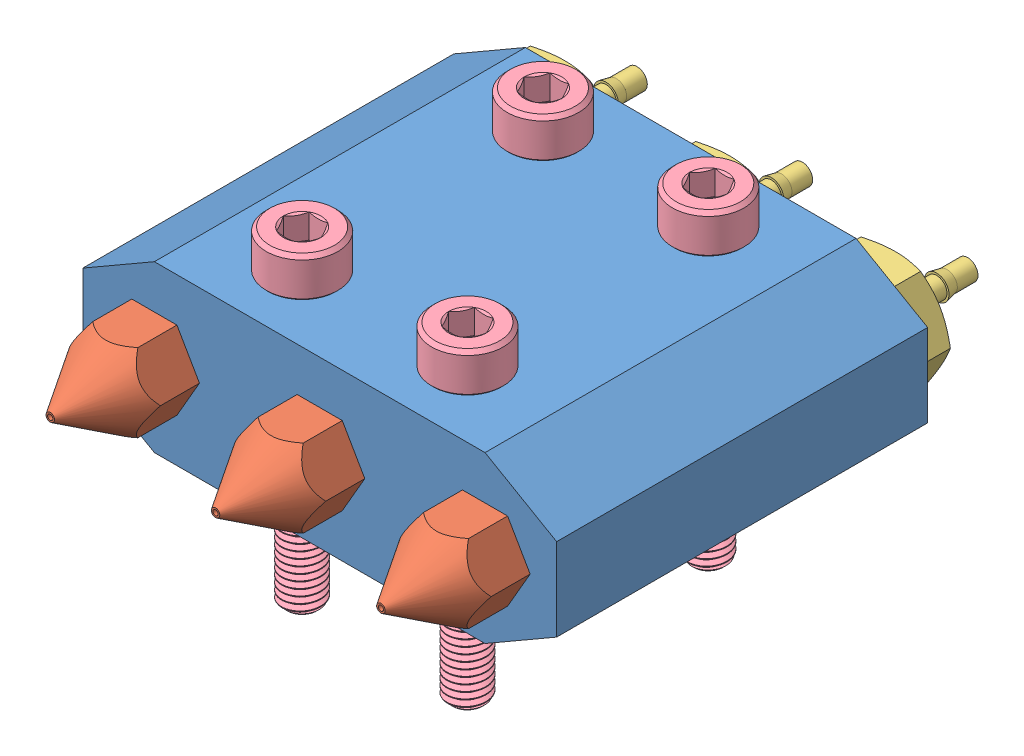
SolidWorks assembly SUB_3 Nozzle Block Assembly, configuration Default. Lengths in mm.
Overall size (36.86 25.38 45.07).
11 component instances, 4 part files, 30 mates.
Components (placement in the parent):
- M22a_3 Nozzle Block-1: M22a_3 Nozzle Block [Default] at (-7.7246 28.2 32.9307) size (36.4 12.7 28.5)
- M20_Creality Brass Nozzle-1: M20_Creality Brass Nozzle [Default] at (-1.3746 34.55 40.9307) x (0.866025 0.5 0) z (0 0 1) size (6 7.32 13)
- M20_Creality Brass Nozzle-2: M20_Creality Brass Nozzle [Default] at (11.3254 34.55 40.9307) x (0.866025 0.5 0) z (0 0 1) size (6 7.32 13)
- M20_Creality Brass Nozzle-3: M20_Creality Brass Nozzle [Default] at (24.0254 34.55 40.9307) x (0.866025 0.5 0) z (0 0 1) size (6 7.32 13)
- M21_5058K956_ALUMINUM LOW-PRESSURE BARBED TUBE FITTING-1: M21_5058K956_ALUMINUM LOW-PRESSURE BARBED TUBE FITTING [5058K956] at (24.0254 34.55 3.3988) x (0 0 -1) z (0.866025 0.5 0) size (15.08 9.17 7.94)
- M21_5058K956_ALUMINUM LOW-PRESSURE BARBED TUBE FITTING-2: M21_5058K956_ALUMINUM LOW-PRESSURE BARBED TUBE FITTING [5058K956] at (-1.3746 34.55 3.3988) x (0 0 -1) z (0.866025 0.5 0) size (15.08 9.17 7.94)
- M21_5058K956_ALUMINUM LOW-PRESSURE BARBED TUBE FITTING-4: M21_5058K956_ALUMINUM LOW-PRESSURE BARBED TUBE FITTING [5058K956] at (11.3254 34.55 3.3988) x (0 0 -1) z (0.866025 0.5 0) size (15.08 9.17 7.94)
- M41_91292A801_18-8 Stainless Steel Socket Head Screw-1: M41_91292A801_18-8 Stainless Steel Socket Head Screw [91292A801] at (4.9754 31.4 27.9307) x (0 0 1) z (0 1 0) size (5.5 5.5 25.38)
- M41_91292A801_18-8 Stainless Steel Socket Head Screw-2: M41_91292A801_18-8 Stainless Steel Socket Head Screw [91292A801] at (4.9754 31.4 9.4307) x (0.866025 0 0.5) z (0 1 0) size (5.5 5.5 25.38)
- M41_91292A801_18-8 Stainless Steel Socket Head Screw-3: M41_91292A801_18-8 Stainless Steel Socket Head Screw [91292A801] at (17.6754 31.4 27.9307) x (0 0 1) z (0 1 0) size (5.5 5.5 25.38)
- M41_91292A801_18-8 Stainless Steel Socket Head Screw-4: M41_91292A801_18-8 Stainless Steel Socket Head Screw [91292A801] at (17.6754 31.4 9.4307) x (-0.866025 0 0.5) z (0 1 0) size (5.5 5.5 25.38)
Mates (geometry in assembly coordinates):
- Concentric1: concentric aligned: cylinder of 3 Nozzle Block-1 through (-1.3746 34.55 32.9307) axis (0 0 1) radius 2.5; cylinder of M20_Creality Brass Nozzle-1 through (-1.3746 34.55 40.9307) axis (0 0 1) radius 3
- Coincident1: coincident anti-aligned: plane of 3 Nozzle Block-1 through (-7.7246 28.2 32.9307) normal (0 0 1); plane of M20_Creality Brass Nozzle-1 through (-3.1067 37.55 32.9307) normal (0 0 -1)
- Parallel1: parallel aligned: plane of 3 Nozzle Block-1 through (-7.7246 40.9 4.4307) normal (0 1 0); plane of M20_Creality Brass Nozzle-1 through (0.3574 37.55 27.9307) normal (0 1 0)
- Concentric2: concentric aligned: cylinder of 3 Nozzle Block-1 through (11.3254 34.55 32.9307) axis (0 0 1) radius 2.5; cylinder of M20_Creality Brass Nozzle-2 through (11.3254 34.55 40.9307) axis (0 0 1) radius 3
- Coincident3: coincident anti-aligned: plane of 3 Nozzle Block-1 through (-7.7246 28.2 32.9307) normal (0 0 1); plane of M20_Creality Brass Nozzle-2 through (9.5933 37.55 32.9307) normal (0 0 -1)
- Parallel2: parallel aligned: plane of 3 Nozzle Block-1 through (-7.7246 40.9 4.4307) normal (0 1 0); plane of M20_Creality Brass Nozzle-2 through (13.0574 37.55 27.9307) normal (0 1 0)
- Concentric3: concentric aligned: cylinder of 3 Nozzle Block-1 through (24.0254 34.55 32.9307) axis (0 0 1) radius 2.5; cylinder of M20_Creality Brass Nozzle-3 through (24.0254 34.55 40.9307) axis (0 0 1) radius 3
- Coincident5: coincident anti-aligned: plane of 3 Nozzle Block-1 through (-7.7246 28.2 32.9307) normal (0 0 1); plane of M20_Creality Brass Nozzle-3 through (22.2933 37.55 32.9307) normal (0 0 -1)
- Parallel3: parallel aligned: plane of M20_Creality Brass Nozzle-3 through (25.7574 37.55 27.9307) normal (0 1 0); plane of 3 Nozzle Block-1 through (-7.7246 40.9 4.4307) normal (0 1 0)
- Concentric4: concentric aligned: cylinder of 3 Nozzle Block-1 through (24.0254 34.55 32.9307) axis (0 0 1) radius 2.5; cylinder of M21_5058K956_ALUMINUM LOW-PRESSURE BARBED TUBE FITTING-1 through (24.0254 34.55 -4.0546) axis (0 0 1) radius 3
- Parallel4: parallel aligned: plane of M21_5058K956_ALUMINUM LOW-PRESSURE BARBED TUBE FITTING-1 through (21.734 38.5187 4.4307) normal (0 1 0); plane of 3 Nozzle Block-1 through (-7.7246 40.9 4.4307) normal (0 1 0)
- Coincident8: coincident anti-aligned: plane of 3 Nozzle Block-1 through (-7.7246 28.2 4.4307) normal (0 0 -1); plane of M21_5058K956_ALUMINUM LOW-PRESSURE BARBED TUBE FITTING-1 through (24.0254 42.4875 4.4307) normal (0 0 1)
- Concentric5: concentric aligned: cylinder of 3 Nozzle Block-1 through (11.3254 34.55 32.9307) axis (0 0 1) radius 2.5; cylinder of M21_5058K956_ALUMINUM LOW-PRESSURE BARBED TUBE FITTING-4 through (11.3254 34.55 -4.0546) axis (0 0 1) radius 3
- Coincident10: coincident anti-aligned: plane of 3 Nozzle Block-1 through (-7.7246 28.2 4.4307) normal (0 0 -1); plane of M21_5058K956_ALUMINUM LOW-PRESSURE BARBED TUBE FITTING-4 through (11.3254 42.4875 4.4307) normal (0 0 1)
- Parallel5: parallel aligned: plane of 3 Nozzle Block-1 through (-7.7246 40.9 4.4307) normal (0 1 0); plane of M21_5058K956_ALUMINUM LOW-PRESSURE BARBED TUBE FITTING-4 through (9.034 38.5187 4.4307) normal (0 1 0)
- Concentric6: concentric aligned: cylinder of 3 Nozzle Block-1 through (-1.3746 34.55 32.9307) axis (0 0 1) radius 2.5; cylinder of M21_5058K956_ALUMINUM LOW-PRESSURE BARBED TUBE FITTING-2 through (-1.3746 34.55 -4.0546) axis (0 0 1) radius 3
- Coincident12: coincident anti-aligned: plane of 3 Nozzle Block-1 through (-7.7246 28.2 4.4307) normal (0 0 -1); plane of M21_5058K956_ALUMINUM LOW-PRESSURE BARBED TUBE FITTING-2 through (-1.3746 42.4875 4.4307) normal (0 0 1)
- Parallel6: parallel aligned: plane of 3 Nozzle Block-1 through (-7.7246 40.9 4.4307) normal (0 1 0); plane of M21_5058K956_ALUMINUM LOW-PRESSURE BARBED TUBE FITTING-2 through (-3.666 38.5187 4.4307) normal (0 1 0)
- Concentric7: concentric anti-aligned: cylinder of M22a_3 Nozzle Block-1 through (4.9754 28.2 27.9307) axis (0 1 0) radius 1.55; cylinder of M41_91292A801_18-8 Stainless Steel Socket Head Screw-1 through (4.9754 18.9 27.9307) axis (0 -1 0) radius 2.75
- Coincident13: coincident anti-aligned: plane of M22a_3 Nozzle Block-1 through (-7.7246 40.9 4.4307) normal (0 1 0); plane of M41_91292A801_18-8 Stainless Steel Socket Head Screw-1 through (4.9754 40.9 25.3182) normal (0 -1 0)
- Parallel7: parallel aligned: plane of M22a_3 Nozzle Block-1 through (-7.7246 28.2 32.9307) normal (0 0 1); plane of M41_91292A801_18-8 Stainless Steel Socket Head Screw-1 through (5.6971 42.025 26.6807) normal (0 0 1)
- Concentric8: concentric anti-aligned: cylinder of M22a_3 Nozzle Block-1 through (4.9754 28.2 9.4307) axis (0 1 0) radius 1.55; cylinder of M41_91292A801_18-8 Stainless Steel Socket Head Screw-2 through (4.9754 18.9 9.4307) axis (0 -1 0) radius 2.75
- Coincident15: coincident anti-aligned: plane of M22a_3 Nozzle Block-1 through (-7.7246 40.9 4.4307) normal (0 1 0); plane of M41_91292A801_18-8 Stainless Steel Socket Head Screw-2 through (2.7129 40.9 8.1245) normal (0 -1 0)
- Parallel8: parallel anti-aligned: plane of M22a_3 Nozzle Block-1 through (-7.7246 28.2 32.9307) normal (0 0 1); plane of M41_91292A801_18-8 Stainless Steel Socket Head Screw-2 through (4.2537 42.025 10.6807) normal (0 0 -1)
- Concentric10: concentric anti-aligned: cylinder of M22a_3 Nozzle Block-1 through (17.6754 28.2 27.9307) axis (0 1 0) radius 1.55; cylinder of M41_91292A801_18-8 Stainless Steel Socket Head Screw-3 through (17.6754 18.9 27.9307) axis (0 -1 0) radius 2.75
- Coincident17: coincident anti-aligned: plane of M22a_3 Nozzle Block-1 through (-7.7246 40.9 4.4307) normal (0 1 0); plane of M41_91292A801_18-8 Stainless Steel Socket Head Screw-3 through (17.6754 40.9 25.3182) normal (0 -1 0)
- Parallel9: parallel anti-aligned: plane of M22a_3 Nozzle Block-1 through (-7.7246 28.2 32.9307) normal (0 0 1); plane of M41_91292A801_18-8 Stainless Steel Socket Head Screw-3 through (16.9537 42.025 29.1807) normal (0 0 -1)
- Concentric11: concentric anti-aligned: cylinder of M22a_3 Nozzle Block-1 through (17.6754 28.2 9.4307) axis (0 1 0) radius 1.55; cylinder of M41_91292A801_18-8 Stainless Steel Socket Head Screw-4 through (17.6754 18.9 9.4307) axis (0 -1 0) radius 2.75
- Coincident19: coincident anti-aligned: plane of M22a_3 Nozzle Block-1 through (-7.7246 40.9 4.4307) normal (0 1 0); plane of M41_91292A801_18-8 Stainless Steel Socket Head Screw-4 through (19.9379 40.9 8.1245) normal (0 -1 0)
- Parallel10: parallel aligned: plane of M22a_3 Nozzle Block-1 through (-7.7246 28.2 32.9307) normal (0 0 1); plane of M41_91292A801_18-8 Stainless Steel Socket Head Screw-4 through (18.3971 42.025 8.1807) normal (0 0 1)
